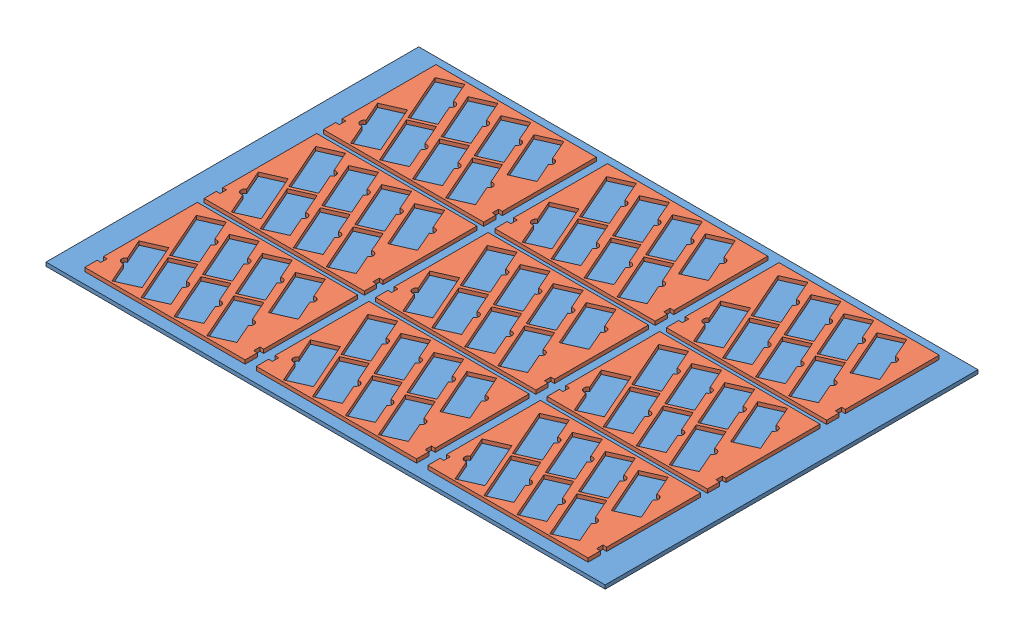
SolidWorks assembly final-darb-9, configuration Default. Lengths in mm.
Overall size (1500 20 1000).
10 component instances, 2 part files, 3 mates.
Components (placement in the parent):
- plate-1: plate [Default] at (629.3908 823.6483 1086.9502) size (1500 10 1000)
- darb-2: darb [Default] at (168.7211 843.6483 766.2345) size (430 10 302)
- darb-3: darb [Default] at (628.7211 843.6483 766.2345) size (430 10 302)
- darb-4: darb [Default] at (1088.7211 843.6483 766.2345) size (430 10 302)
- darb-5: darb [Default] at (168.7211 843.6483 1086.2345) size (430 10 302)
- darb-6: darb [Default] at (168.7211 843.6483 1406.2345) size (430 10 302)
- darb-7: darb [Default] at (628.7211 843.6483 1086.2345) size (430 10 302)
- darb-8: darb [Default] at (628.7211 843.6483 1406.2345) size (430 10 302)
- darb-9: darb [Default] at (1088.7211 843.6483 1086.2345) size (430 10 302)
- darb-10: darb [Default] at (1088.7211 843.6483 1406.2345) size (430 10 302)
Mates (geometry in assembly coordinates):
- Coincident4: coincident anti-aligned: plane of plate-1 through (629.3908 833.6483 1086.9502) normal (0 1 0); plane of darb-2 through (168.7211 833.6483 766.2345) normal (0 -1 0)
- Distance13: distance = 75 mm: line of darb-2 through (-46.2789 843.6483 867.2345) axis (0 0 -1); line of plate-1 through (-120.6092 833.6483 586.9502) axis (0 0 1)
- Distance14: distance = 30 mm: line of darb-2 through (-46.2789 843.6483 615.2345) axis (1 0 0); line of plate-1 through (1379.3908 833.6483 586.9502) axis (-1 0 0)
